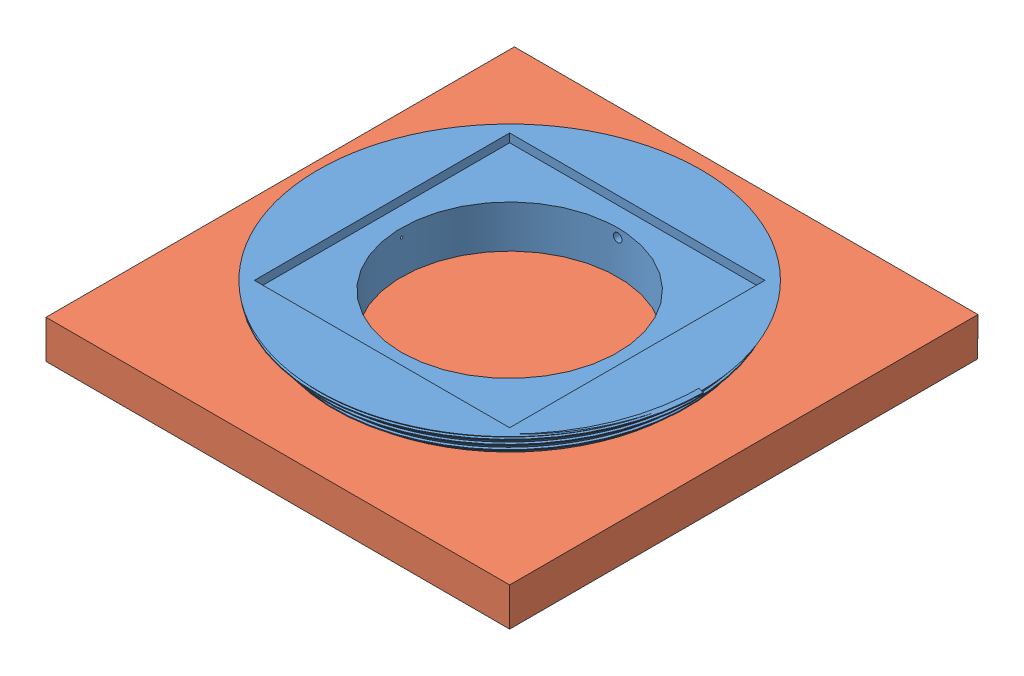
SolidWorks assembly ASIteration2, configuration Default. Lengths in mm.
Overall size (55 9.26 55.04).
2 component instances, 2 part files, 12 mates.
Components (placement in the parent):
- innerCircleIteration2-1: innerCircleIteration2 [Default] at origin size (50.15 8.07 52.92)
- Part7-1: Part7 [Default] x (-1 0 0) z (0 -1 0) size (55 55.04 4.63)
Mates (geometry in assembly coordinates):
- InPlace1: in place: plane of innerCircleIteration2-1 through (0 0 0) normal (0 -1 0); plane of Part7-1 through (0 0 0) normal (0 -1 0); moOrthogonalPlaneRef_w of innerCircleIteration2-1 through (0 0 0) normal (0 -1 0); unknown of Part7-1; plane of innerCircleIteration2-1 through (0 0 0) normal (0 -1 0); line of Part7-1 through (55 -55 0) axis (0 0 -1); plane of innerCircleIteration2-1 through (0 0 0) normal (0 -1 0); unknown of Part7-1
- Coincident1: coincident aligned: plane of innerCircleIteration2-1; plane of ?
- Coincident2: coincident aligned: moOrthogonalPlaneRef_w of innerCircleIteration2-1 through (0 0 0) normal (0 0 -1); plane of Part7-1
- Coincident3: coincident anti-aligned: moOrthogonalPlaneRef_w of innerCircleIteration2-1 through (0 0 0) normal (1 0 0); plane of Part7-1
- InPlace2: in place: plane of innerCircleIteration2-1 through (0 6 0) normal (0 1 0); plane of ? through (0 6 0) normal (0 1 0); plane of innerCircleIteration2-1 through (0 6 0) normal (0 1 0); plane of ? through (0 6 0) normal (0 0 -1); plane of innerCircleIteration2-1 through (0 6 0) normal (0 1 0); line of ? through (-55 0 6) axis (0 1 0); plane of innerCircleIteration2-1 through (0 6 0) normal (0 1 0); unknown of ?
- Coincident4: coincident aligned: plane of innerCircleIteration2-1; plane of ?
- Coincident5: coincident aligned: moOrthogonalPlaneRef_w of innerCircleIteration2-1 through (0 6 0) normal (0 0 -1); plane of ? through (0 6 0) normal (0 0 -1)
- Coincident6: coincident anti-aligned: moOrthogonalPlaneRef_w of innerCircleIteration2-1 through (0 6 0) normal (-1 0 0); plane of ?
- InPlace3: in place: plane of innerCircleIteration2-1 through (0 0 0) normal (0 -1 0); plane of Part7-1 through (0 0 0) normal (0 -1 0); plane of innerCircleIteration2-1 through (0 0 0) normal (0 -1 0); unknown of Part7-1; plane of innerCircleIteration2-1 through (0 0 0) normal (0 -1 0); line of Part7-1 through (55 -55 0) axis (0 0 -1); plane of innerCircleIteration2-1 through (0 0 0) normal (0 -1 0); unknown of Part7-1
- Coincident7: coincident aligned: plane of innerCircleIteration2-1; plane of Part7-1
- Coincident8: coincident aligned: moOrthogonalPlaneRef_w of innerCircleIteration2-1 through (0 0 0) normal (0 0 -1); plane of Part7-1
- Coincident9: coincident anti-aligned: moOrthogonalPlaneRef_w of innerCircleIteration2-1 through (0 0 0) normal (1 0 0); plane of Part7-1
